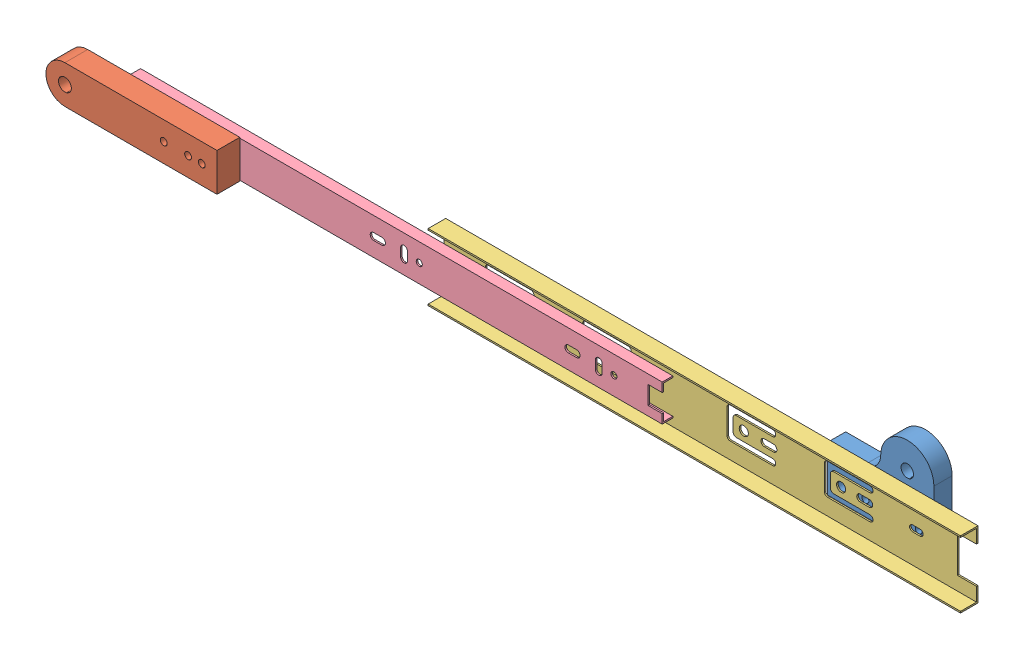
SolidWorks assembly 滑轨装配体-镜像, configuration 默认. Lengths in mm.
Overall size (585.89 69.5 39).
5 component instances, 4 part files, 6 mates.
Components (placement in the parent):
- 滑轨转动副1-1: 滑轨转动副1 [默认] at (-14.7387 -9.0935 64) size (70 57.5 12)
- 滑轨转动副2-1: 滑轨转动副2 [默认] at (-467.2969 -11.5548 88) size (112.5 25 15)
- 滑轨装配体-1: 滑轨装配体 [默认] at (-475.7387 -8.3173 80.0623) x (0 1 0) z (1 0 0) size (44 12 545.64) (flexible)
  - 滑轨1-1: 滑轨1 [默认] at (6.4098 2.026 175) size (44 11.5 350)
  - 滑轨2-1: 滑轨2 [默认] at (-5.7763 4.4377 329.3636) x (1 0 0) z (0 0 -1) size (24 7 350)
Mates (geometry in assembly coordinates):
- 同心1: concentric aligned: cylinder of 滑轨转动副1-1 through (-39.7387 -14.0935 76) axis (0 0 -1) radius 3; cylinder of 滑轨装配体-1/滑轨1-1 through (-39.7387 -14.0935 426) axis (0 0 -1) radius 3
- 重合1: coincident anti-aligned: plane of 滑轨转动副1-1 through (2.7613 15.9065 76) normal (0 0 1); plane of 滑轨装配体-1/滑轨1-1 through (49.2613 -36.0935 76) normal (0 0 -1)
- 相切2: tangent anti-aligned: cylinder of 滑轨转动副1-1 through (-24.7387 -14.0935 76) axis (0 0 -1) radius 2.25; plane of 滑轨装配体-1/滑轨1-1 through (-21.2387 -16.3435 426) normal (0 1 0)
- 同心2: concentric anti-aligned: cylinder of 滑轨转动副2-1 through (-434.1252 -14.0935 103) axis (0 0 -1) radius 2.25; cylinder of 滑轨装配体-1/滑轨2-1 through (-434.1252 -14.0935 -3412) axis (0 0 1) radius 2
- 重合2: coincident anti-aligned: plane of 滑轨转动副2-1 through (-524.1252 -14.0935 88) normal (0 0 -1); plane of 滑轨装配体-1/滑轨2-1 through (-496.3752 -26.0935 88) normal (0 0 1)
- 相切3: tangent anti-aligned: cylinder of 滑轨转动副2-1 through (-459.1252 -14.0935 103) axis (0 0 -1) radius 2.25; plane of 滑轨装配体-1/滑轨2-1 through (-464.1252 -16.3435 -3412) normal (0 1 0)
